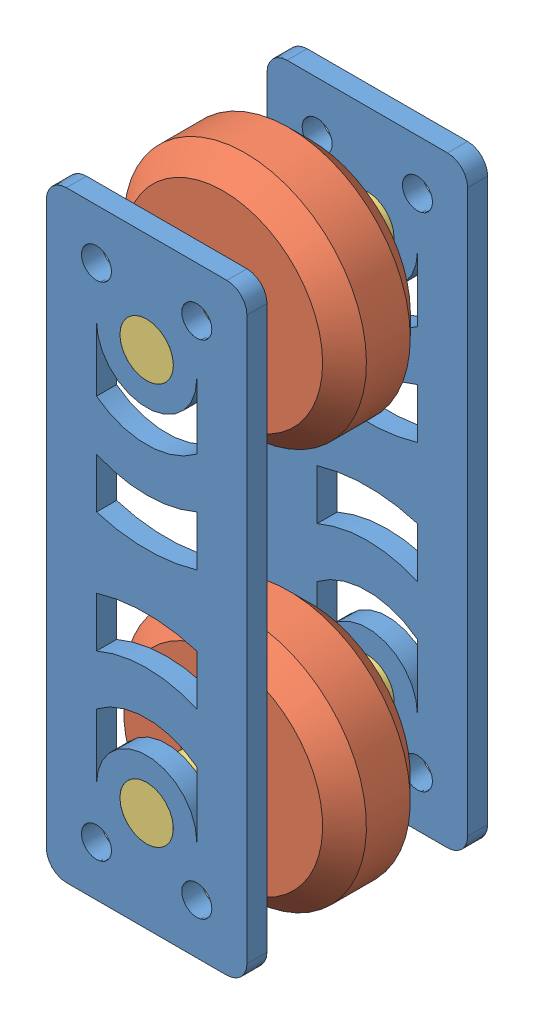
SolidWorks assembly Gantry Slider, configuration Default. Lengths in mm.
Overall size (42.64 93.3 30.48).
6 component instances, 3 part files, 11 mates.
Components (placement in the parent):
- Gantry Slide-1: Gantry Slide [Default] at (3.4077 42.2553 68.7394) size (25.4 76.2 2.54)
- Gantry Slide-2: Gantry Slide [Default] at (3.4077 42.2553 40.7994) size (25.4 76.2 2.54)
- V-Slot Bearing Stand-In-1: V-Slot Bearing Stand-In [Default] at (3.4077 67.6553 50.4894) x (0.557143 0.830417 0) z (0.830417 -0.557143 0) size (30.73 11.1 30.73)
- V-Slot Bearing Stand-In-2: V-Slot Bearing Stand-In [Default] at (3.4077 16.8553 50.4894) x (0.846745 0.531999 0) z (0.531999 -0.846745 0) size (30.73 11.1 30.73)
- Gantry Standoff-1: Gantry Standoff [Default] at (3.4077 67.6553 40.7994) x (-0.062309 -0.998057 0) z (0 0 1) size (6.77 6.77 30.48)
- Gantry Standoff-2: Gantry Standoff [Default] at (3.4077 16.8553 40.7994) x (0.070018 -0.997546 0) z (0 0 1) size (6.77 6.77 30.48)
Mates (geometry in assembly coordinates):
- Concentric1: concentric anti-aligned: cylinder of Gantry Slide-1 through (3.4077 67.6553 68.7394) axis (0 0 1) radius 3.3858; cylinder of V-Slot Bearing Stand-In-1 through (3.4077 67.6553 61.5894) axis (0 0 -1) radius 4.7625
- Concentric2: concentric aligned: cylinder of Gantry Slide-1 through (3.4077 67.6553 68.7394) axis (0 0 1) radius 3.3858; cylinder of Gantry Slide-2 through (3.4077 67.6553 40.7994) axis (0 0 1) radius 3.3858
- Concentric3: concentric anti-aligned: cylinder of Gantry Slide-1 through (3.4077 16.8553 68.7394) axis (0 0 1) radius 3.3858; cylinder of V-Slot Bearing Stand-In-2 through (3.4077 16.8553 61.5894) axis (0 0 -1) radius 4.7625
- Concentric4: concentric aligned: cylinder of Gantry Slide-1 through (3.4077 16.8553 68.7394) axis (0 0 1) radius 3.3858; cylinder of Gantry Slide-2 through (3.4077 16.8553 40.7994) axis (0 0 1) radius 3.3858
- Distance1: distance = 25.4 mm anti-aligned: plane of Gantry Slide-2 through (3.4077 42.2553 43.3394) normal (0 0 1); plane of Gantry Slide-1 through (3.4077 42.2553 68.7394) normal (0 0 -1)
- Coincident2: coincident aligned: plane of V-Slot Bearing Stand-In-1 through (3.4077 67.6553 61.5894) normal (0 0 1); plane of V-Slot Bearing Stand-In-2 through (3.4077 16.8553 61.5894) normal (0 0 1)
- Distance2: distance = 7.15 mm anti-aligned: plane of Gantry Slide-1 through (3.4077 42.2553 68.7394) normal (0 0 -1); plane of V-Slot Bearing Stand-In-1 through (3.4077 67.6553 61.5894) normal (0 0 1)
- Concentric5: concentric anti-aligned: cylinder of Gantry Slide-2 through (3.4077 16.8553 40.7994) axis (0 0 1) radius 3.3858; cylinder of Gantry Standoff-2 through (3.4077 16.8553 71.2794) axis (0 0 -1) radius 3.3858
- Coincident4: coincident aligned: plane of Gantry Slide-2 through (3.4077 42.2553 40.7994) normal (0 0 -1); plane of Gantry Standoff-2 through (3.4077 16.8553 40.7994) normal (0 0 -1)
- Concentric6: concentric anti-aligned: cylinder of Gantry Slide-2 through (3.4077 67.6553 40.7994) axis (0 0 1) radius 3.3858; cylinder of Gantry Standoff-1 through (3.4077 67.6553 71.2794) axis (0 0 -1) radius 3.3858
- Coincident5: coincident aligned: plane of Gantry Slide-2 through (3.4077 42.2553 40.7994) normal (0 0 -1); plane of Gantry Standoff-1 through (3.4077 67.6553 40.7994) normal (0 0 -1)
